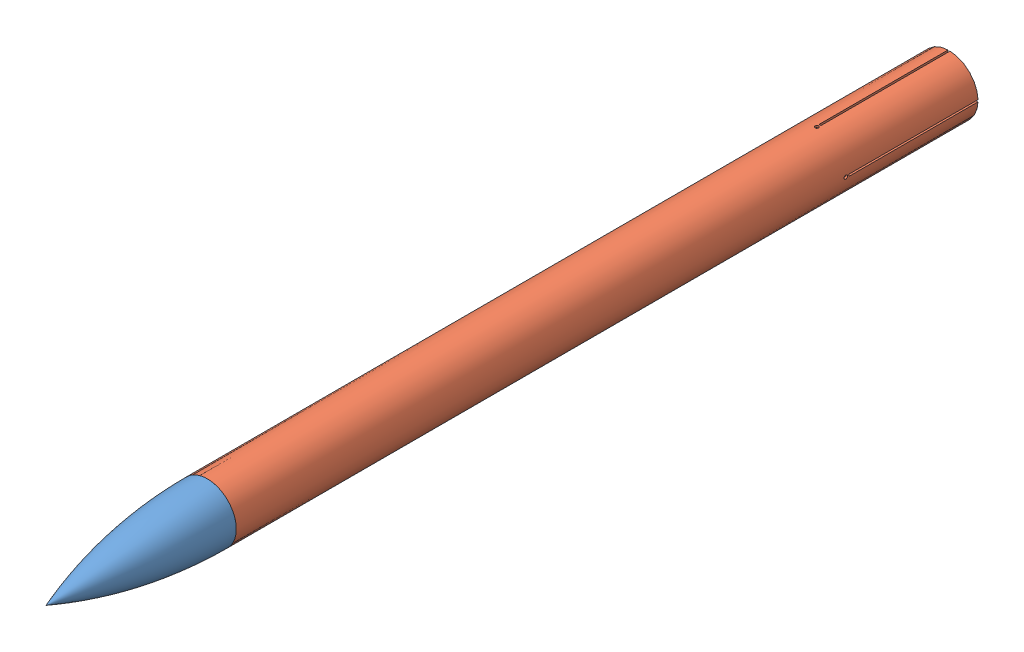
SolidWorks assembly 1. SA CORP, configuration Défaut. Lengths in mm.
Overall size (156.97 613.09 1400).
3 component instances, 3 part files, 2 mates.
Components (placement in the parent):
- Tube Bas-1: Tube Bas [Défaut] at (-52.7749 0.6656 650) size (104.2 90 150)
- ogive 1bis-1: ogive 1bis [Défaut] at (0 523.7598 848.0373) x (0 0 -1) z (1 0 0) size (250 90 90)
- Tube supérieur-1: Tube supérieur [Défaut] at (0 523.7598 -551.9627) size (151.89 90 1150)
Mates (geometry in assembly coordinates):
- Coïncidente3: coincident aligned: circle of ogive 1bis-1; cylinder of Tube supérieur-1 through (0 523.7598 598.0373) axis (0 0 -1) radius 42
- Coïncidente4: coincident anti-aligned: plane of ogive 1bis-1 through (-45 523.7598 598.0373) normal (0 0 -1); plane of Tube supérieur-1 through (0 523.7598 598.0373) normal (0 0 1)
